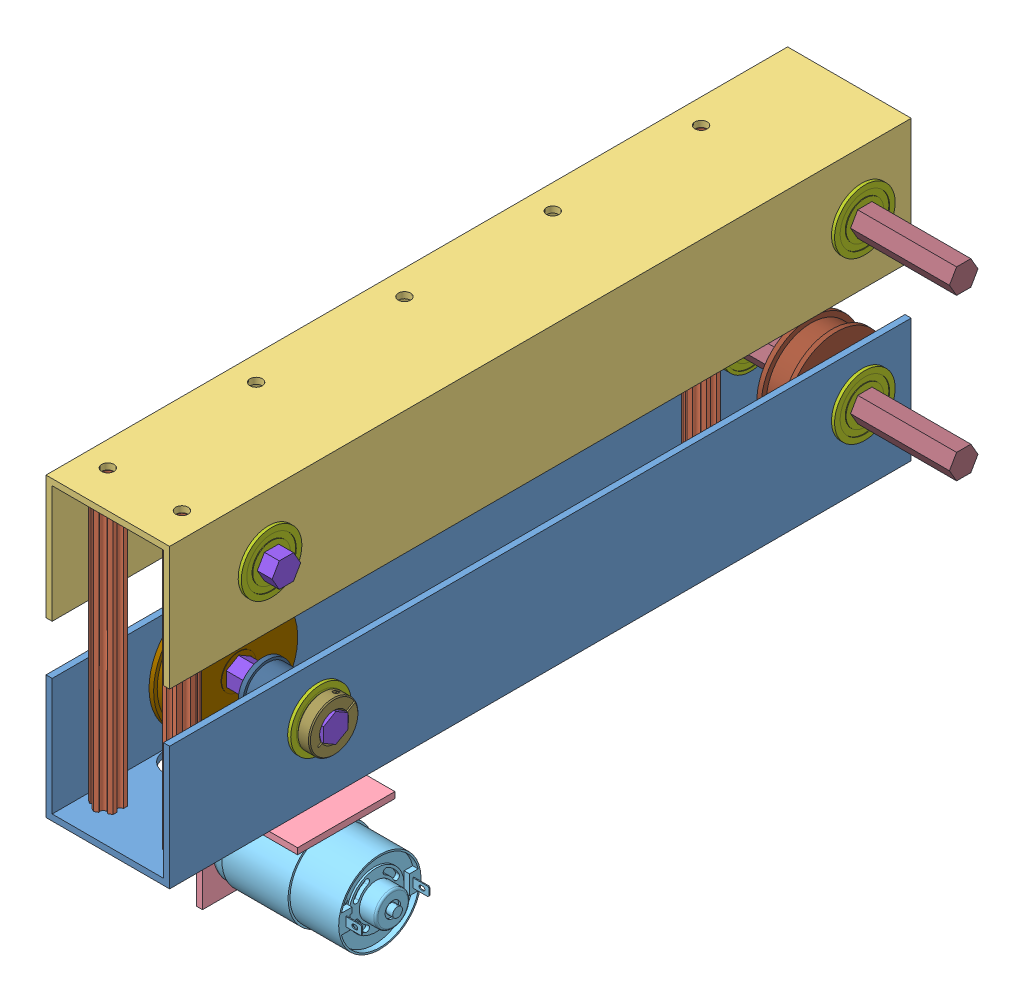
SolidWorks assembly 2018-402-A, configuration Default. Lengths in mm.
Overall size (127 204.4 381.04).
28 component instances, 13 part files, 80 mates.
Components (placement in the parent):
- 2018-402-D004-1: 2018-402-D004 [Default] at (114.5384 101.9763 135.5684) size (63.5 63.5 381)
- 2018-402-D021-1: 2018-402-D021 [Default] at (127.2384 251.2013 497.5184) x (0 0 -1) z (0 -1 0) size (14.66 12.7 146.05)
- 2018-402-D021-2: 2018-402-D021 [Default] at (165.3384 251.2013 497.5184) x (1 0 0) z (0 -1 0) size (14.66 12.7 146.05)
- 2018-402-D021-3: 2018-402-D021 [Default] at (127.2384 251.2013 192.7184) x (0 0 -1) z (0 -1 0) size (14.66 12.7 146.05)
- 2018-402-D005-2: 2018-402-D005 [Default] at (178.0384 254.3763 135.5684) x (-1 0 0) z (0 0 1) size (63.5 63.5 381)
- 2018-402-D014-1: 2018-402-D014 [Default] at (140.5734 49.9763 465.3684) x (0 0 -1) z (-1 0 0) size (68.52 52 56.75)
- 2018-402-D013-2: 2018-402-D013 [Default] at (143.7484 73.9763 440.3684) x (1 0 0) z (0 -1 0) size (88 44.3 44.3)
- 2018-402-D016-1: 2018-402-D016 [Default] at (137.5038 73.9763 440.3684) x (0 -1 0) z (0 0 1) size (15.01 17.5 15.01)
- 2018-403-D005-1: 2018-403-D005 [Default] at (120.8884 140.0763 440.3684) x (0 -1 0) z (0 0 -1) size (31.12 7.94 31.12)
- 2018-403-D005-2: 2018-403-D005 [Default] at (171.6884 140.0763 440.3684) x (0 -1 0) z (0 0 1) size (31.12 7.94 31.12)
- 2018-402-D025-1: 2018-402-D025 [Default] at (103.4259 140.0936 440.3584) x (0 -0.5 -0.866025) z (0 -0.866025 0.5) size (14.66 83.82 12.7)
- 2018-402-D019-1: 2018-402-D019 [Default] at (140.501 140.0936 440.2568) x (0 -1 0) z (0 0 1) size (61.01 15.88 61.01)
- 2018-402-D017-1: 2018-402-D017 [Default] at (168.5515 140.0643 440.3076) x (0 -1 0) z (0 0 1) size (25.4 15.88 25.4)
- 2018-403-D005-5: 2018-403-D005 [Default] at (120.8884 140.0763 160.9684) x (0 0 1) z (0 -1 0) size (31.12 7.94 31.12)
- 2018-403-D005-6: 2018-403-D005 [Default] at (171.6884 140.0763 160.9684) x (0 -0.866025 0.5) z (0 0.5 0.866025) size (31.12 7.94 31.12)
- 2018-402-D025-3: 2018-402-D025 [Default] at (100.2509 140.0863 160.9742) x (0 0 -1) z (0 -1 0) size (14.66 83.82 12.7) (hidden)
- 2018-402-D018-1: 2018-402-D018 [Default] at (168.5515 140.0863 161.0329) x (0 0 -1) z (0 -1 0) size (51 15.88 51)
- 2018-403-D005-7: 2018-403-D005 [Default] at (120.8884 222.6263 465.7684) x (0 0 1) z (0 -1 0) size (31.12 7.94 31.12)
- 2018-403-D005-8: 2018-403-D005 [Default] at (171.6884 222.6263 465.7684) x (0 -0.866025 -0.5) z (0 -0.5 0.866025) size (31.12 7.94 31.12)
- 2018-403-D002-1: 2018-403-D002 [Default] at (109.0742 140.1669 440.2314) x (0 -0.5 -0.866025) z (1 0 0) size (25.39 25.4 7.82)
- 2018-403-D002-2: 2018-403-D002 [Default] at (183.0549 139.8736 440.2314) x (0 0.5 -0.866025) z (1 0 0) size (25.39 25.4 7.82)
- 2018-402-D023-2: 2018-402-D023 [Default] at (103.4259 140.0863 160.9742) x (0 0.866025 -0.5) z (0 -0.5 -0.866025) size (14.66 127 12.7)
- 2018-403-D002-3: 2018-403-D002 [Default] at (109.5219 140.2133 161.0475) x (0 -0.866025 -0.5) z (1 0 0) size (25.39 25.4 7.82)
- 2018-402-D025-4: 2018-402-D025 [Default] at (187.2459 222.6163 465.7627) x (0 -0.866025 0.5) z (0 -0.5 -0.866025) size (14.66 83.82 12.7)
- 2018-403-D005-9: 2018-403-D005 [Default] at (171.6884 222.6263 160.9684) x (0 0 1) z (0 1 0) size (31.12 7.94 31.12)
- 2018-403-D005-10: 2018-403-D005 [Default] at (120.8884 222.6263 160.9684) x (0 0 1) z (0 -1 0) size (31.12 7.94 31.12)
- 2018-402-D023-3: 2018-402-D023 [Default] at (230.4259 222.6163 160.9742) x (0 -0.866025 -0.5) z (0 0.5 -0.866025) size (14.66 127 12.7)
- 2018-403-D002-4: 2018-403-D002 [Default] at (109.5219 222.6163 465.9093) x (0 -0.866025 -0.5) z (-1 0 0) size (25.39 25.4 7.82)
Mates (geometry in assembly coordinates):
- Concentric1: concentric anti-aligned: cylinder of 2018-402-D004-1 through (127.2384 165.4763 497.5184) axis (0 -1 0) radius 3.175; cylinder of 2018-402-D021-1 through (127.2384 -53.5987 497.5184) axis (0 1 0) radius 2.9337
- Coincident1: coincident anti-aligned: plane of 2018-402-D004-1 through (117.7134 105.1513 516.5684) normal (0 1 0); plane of 2018-402-D021-1 through (130.4134 105.1513 492.0192) normal (0 -1 0)
- Parallel1: parallel anti-aligned: plane of 2018-402-D004-1 through (114.5384 101.9763 516.5684) normal (-1 0 0); plane of 2018-402-D021-1 through (127.2384 251.2013 497.5184) normal (1 0 0)
- Concentric2: concentric anti-aligned: cylinder of 2018-402-D004-1 through (165.3384 165.4763 497.5184) axis (0 -1 0) radius 3.175; cylinder of 2018-402-D021-2 through (165.3384 -53.5987 497.5184) axis (0 1 0) radius 2.9337
- Coincident3: coincident anti-aligned: plane of 2018-402-D004-1 through (117.7134 105.1513 516.5684) normal (0 1 0); plane of 2018-402-D021-2 through (170.8377 105.1513 500.6934) normal (0 -1 0)
- Parallel2: parallel anti-aligned: plane of 2018-402-D004-1 through (114.5384 101.9763 516.5684) normal (-1 0 0); plane of 2018-402-D021-2 through (165.3384 251.2013 497.5184) normal (1 0 0)
- Concentric3: concentric anti-aligned: cylinder of 2018-402-D004-1 through (127.2384 165.4763 192.7184) axis (0 -1 0) radius 3.175; cylinder of 2018-402-D021-3 through (127.2384 -53.5987 192.7184) axis (0 1 0) radius 2.9337
- Coincident5: coincident anti-aligned: plane of 2018-402-D004-1 through (117.7134 105.1513 516.5684) normal (0 1 0); plane of 2018-402-D021-3 through (130.4134 105.1513 187.2192) normal (0 -1 0)
- Parallel3: parallel anti-aligned: plane of 2018-402-D004-1 through (114.5384 101.9763 516.5684) normal (-1 0 0); plane of 2018-402-D021-3 through (127.2384 251.2013 192.7184) normal (1 0 0)
- Concentric4: concentric aligned: cylinder of 2018-402-D021-2 through (165.3384 -53.5987 497.5184) axis (0 1 0) radius 2.9337; cylinder of 2018-402-D005-2 through (165.3384 190.8763 497.5184) axis (0 1 0) radius 3.175
- Coincident7: coincident anti-aligned: plane of 2018-402-D021-2 through (170.8377 251.2013 500.6934) normal (0 1 0); plane of 2018-402-D005-2 through (174.8634 251.2013 516.5684) normal (0 -1 0)
- Concentric5: concentric aligned: cylinder of 2018-402-D021-1 through (127.2384 -53.5987 497.5184) axis (0 1 0) radius 2.9337; cylinder of 2018-402-D005-2 through (127.2384 190.8763 497.5184) axis (0 1 0) radius 3.175
- Coincident11: coincident anti-aligned: plane of 2018-402-D004-1 through (114.5384 101.9763 516.5684) normal (0 -1 0); plane of 2018-402-D014-1 through (140.5734 101.9763 415.3684) normal (0 1 0)
- Coincident14: coincident anti-aligned: plane of 2018-402-D014-1 through (143.7484 98.8013 415.3684) normal (1 0 0); plane of 2018-402-D013-2 through (143.7484 73.9763 449.2684) normal (-1 0 0)
- Concentric9: concentric aligned: cylinder of 2018-402-D014-1 through (192.5734 73.9763 454.8684) axis (-1 0 0) radius 2; cylinder of 2018-402-D013-2 through (143.7484 73.9763 454.8684) axis (-1 0 0) radius 1.65
- Concentric10: concentric aligned: cylinder of 2018-402-D014-1 through (192.5734 73.9763 425.8684) axis (-1 0 0) radius 2; cylinder of 2018-402-D013-2 through (143.7484 73.9763 425.8684) axis (-1 0 0) radius 1.65
- Concentric11: concentric anti-aligned: cylinder of 2018-402-D013-2 through (143.7484 73.9763 440.3684) axis (-1 0 0) radius 2.5; cylinder of 2018-402-D016-1 through (192.5038 73.9763 440.3684) axis (1 0 0) radius 2.286
- Distance3: distance = 0.254 mm anti-aligned: plane of 2018-402-D016-1 through (138.4944 73.9763 438.0824) normal (1 0 0); plane of 2018-402-D013-2 through (138.7484 73.9763 442.8684) normal (-1 0 0)
- Parallel7: parallel aligned: plane of 2018-402-D004-1 through (114.5384 101.9763 516.5684) normal (0 -1 0); plane of 2018-402-D016-1 through (137.5038 73.9763 440.3684) normal (0 -1 0)
- Concentric12: concentric aligned: cylinder of 2018-402-D004-1 through (178.0384 140.0763 440.3684) axis (-1 0 0) radius 14.2875; cylinder of 2018-403-D005-1 through (120.8884 140.0763 440.3684) axis (-1 0 0) radius 14.2748
- Coincident20: coincident anti-aligned: plane of 2018-402-D004-1 through (114.5384 101.9763 516.5684) normal (-1 0 0); plane of 2018-403-D005-1 through (114.5384 124.5188 440.3684) normal (1 0 0)
- Parallel8: parallel aligned: plane of 2018-402-D004-1 through (114.5384 101.9763 516.5684) normal (0 -1 0); plane of 2018-403-D005-1 through (120.8884 140.0763 440.3684) normal (0 -1 0)
- Concentric13: concentric anti-aligned: cylinder of 2018-402-D004-1 through (178.0384 140.0763 440.3684) axis (-1 0 0) radius 14.2875; cylinder of 2018-403-D005-2 through (171.6884 140.0763 440.3684) axis (1 0 0) radius 14.2748
- Coincident22: coincident anti-aligned: plane of 2018-402-D004-1 through (178.0384 165.4763 516.5684) normal (1 0 0); plane of 2018-403-D005-2 through (178.0384 124.5188 440.3684) normal (-1 0 0)
- Parallel9: parallel aligned: plane of 2018-402-D004-1 through (114.5384 101.9763 516.5684) normal (0 -1 0); plane of 2018-403-D005-2 through (171.6884 140.0763 440.3684) normal (0 -1 0)
- Coincident24: coincident anti-aligned: plane of 2018-403-D005-1 through (120.8884 143.7482 446.7284) normal (0 -0.866025 -0.5); plane of 2018-402-D025-1 through (187.2459 147.426 440.3584) normal (0 0.866025 0.5)
- Coincident25: coincident anti-aligned: plane of 2018-403-D005-1 through (120.8884 143.7482 434.0084) normal (0 0 1); plane of 2018-402-D025-1 through (187.2459 136.4274 434.0084) normal (0 0 -1)
- Distance4: distance = 9.525 mm aligned: plane of 2018-402-D025-1 through (103.4259 140.0936 440.3584) normal (-1 0 0); plane of 2018-403-D005-1 through (112.9509 133.7263 440.3684) normal (-1 0 0)
- Coincident27: coincident anti-aligned: plane of 2018-402-D025-1 through (187.2459 136.4274 446.7084) normal (0 -0.866025 0.5); plane of 2018-402-D019-1 through (121.4129 136.3981 446.6576) normal (0 0.866025 -0.5)
- Coincident28: coincident anti-aligned: plane of 2018-402-D025-1 through (187.2459 147.426 440.3584) normal (0 0.866025 0.5); plane of 2018-402-D019-1 through (121.4129 147.4846 440.2568) normal (0 -0.866025 -0.5)
- Distance15: distance = 1.016 mm aligned: plane of 2018-402-D016-1 through (123.0004 73.9763 434.6407) normal (1 0 0); plane of 2018-402-D019-1 through (124.0164 140.0936 411.6056) normal (1 0 0)
- Coincident31: coincident anti-aligned: plane of 2018-402-D025-1 through (187.2459 143.7598 446.7084) normal (0 0 1); plane of 2018-402-D017-1 through (149.4634 143.7598 446.7084) normal (0 0 -1)
- Coincident32: coincident anti-aligned: plane of 2018-402-D025-1 through (187.2459 147.426 440.3584) normal (0 0.866025 0.5); plane of 2018-402-D017-1 through (149.4634 147.4553 440.3076) normal (0 -0.866025 -0.5)
- Distance6: distance = 6.35 mm anti-aligned: plane of 2018-402-D017-1 through (165.3384 140.0643 437.7676) normal (1 0 0); plane of 2018-403-D005-2 through (171.6884 130.4243 440.3684) normal (-1 0 0)
- Concentric16: concentric aligned: cylinder of 2018-402-D004-1 through (266.9384 140.0763 160.9684) axis (-1 0 0) radius 14.2875; cylinder of 2018-403-D005-5 through (120.8884 140.0763 160.9684) axis (-1 0 0) radius 14.2748
- Coincident44: coincident anti-aligned: plane of 2018-402-D004-1 through (114.5384 101.9763 516.5684) normal (-1 0 0); plane of 2018-403-D005-5 through (114.5384 140.0763 176.5259) normal (1 0 0)
- Parallel12: parallel anti-aligned: plane of 2018-402-D004-1 through (114.5384 101.9763 135.5684) normal (0 0 -1); plane of 2018-403-D005-5 through (120.8884 140.0763 160.9684) normal (0 0 1)
- Concentric17: concentric anti-aligned: cylinder of 2018-402-D004-1 through (266.9384 140.0763 160.9684) axis (-1 0 0) radius 14.2875; cylinder of 2018-403-D005-6 through (171.6884 140.0763 160.9684) axis (1 0 0) radius 14.2748
- Coincident46: coincident anti-aligned: plane of 2018-402-D004-1 through (178.0384 165.4763 516.5684) normal (1 0 0); plane of 2018-403-D005-6 through (178.0384 126.6031 168.7472) normal (-1 0 0)
- Coincident47: coincident aligned: plane of 2018-403-D005-5 through (120.8884 140.0763 168.3123) normal (0 -0.5 -0.866025); plane of 2018-403-D005-6 through (171.6884 146.4363 164.6404) normal (0 -0.5 -0.866025)
- Coincident48: coincident anti-aligned: plane of 2018-403-D005-5 through (120.8884 140.0763 168.3123) normal (0 -0.5 -0.866025); plane of 2018-402-D025-3 through (184.0709 146.4363 164.6404) normal (0 0.5 0.866025)
- Coincident49: coincident anti-aligned: plane of 2018-403-D005-5 through (120.8884 146.4363 164.6404) normal (0 -1 0); plane of 2018-402-D025-3 through (184.0709 146.4363 157.308) normal (0 1 0)
- Distance10: distance = 12.7 mm aligned: plane of 2018-402-D025-3 through (100.2509 140.0863 160.9742) normal (-1 0 0); plane of 2018-403-D005-5 through (112.9509 140.0763 167.3184) normal (-1 0 0)
- Coincident51: coincident anti-aligned: plane of 2018-402-D025-3 through (184.0709 133.7363 157.308) normal (0 -0.5 -0.866025); plane of 2018-402-D018-1 through (149.4634 133.6855 157.3374) normal (0 0.5 0.866025)
- Coincident52: coincident anti-aligned: plane of 2018-402-D025-3 through (184.0709 140.0863 153.6419) normal (0 0.5 -0.866025); plane of 2018-402-D018-1 through (149.4634 140.0863 153.6419) normal (0 -0.5 0.866025)
- Coincident53: coincident aligned: plane of 2018-402-D017-1 through (162.7349 140.0643 428.8522) normal (-1 0 0); plane of 2018-402-D018-1 through (162.7349 163.0098 161.0329) normal (-1 0 0)
- Concentric18: concentric aligned: cylinder of 2018-402-D005-2 through (178.0384 222.6263 465.7684) axis (-1 0 0) radius 14.2875; cylinder of 2018-403-D005-7 through (120.8884 222.6263 465.7684) axis (-1 0 0) radius 14.2748
- Coincident54: coincident anti-aligned: plane of 2018-402-D005-2 through (114.5384 190.8763 516.5684) normal (-1 0 0); plane of 2018-403-D005-7 through (114.5384 222.6263 481.3259) normal (1 0 0)
- Parallel13: parallel aligned: plane of 2018-402-D005-2 through (178.0384 254.3763 516.5684) normal (0 0 1); plane of 2018-403-D005-7 through (120.8884 222.6263 465.7684) normal (0 0 1)
- Concentric19: concentric anti-aligned: cylinder of 2018-402-D005-2 through (178.0384 222.6263 465.7684) axis (-1 0 0) radius 14.2875; cylinder of 2018-403-D005-8 through (171.6884 222.6263 465.7684) axis (1 0 0) radius 14.2748
- Coincident56: coincident anti-aligned: plane of 2018-402-D005-2 through (178.0384 254.3763 516.5684) normal (1 0 0); plane of 2018-403-D005-8 through (178.0384 209.1531 457.9897) normal (-1 0 0)
- Coincident57: coincident aligned: plane of 2018-403-D005-7 through (120.8884 222.6263 458.4245) normal (0 0.5 0.866025); plane of 2018-403-D005-8 through (171.6884 216.2663 462.0965) normal (0 0.5 0.866025)
- Coincident58: coincident anti-aligned: plane of 2018-402-D025-1 through (187.2459 143.7598 446.7084) normal (0 0 1); plane of 2018-403-D002-1 through (105.8992 143.9064 446.7084) normal (0 0 -1)
- Coincident59: coincident anti-aligned: plane of 2018-402-D025-1 through (187.2459 136.4274 446.7084) normal (0 -0.866025 0.5); plane of 2018-403-D002-1 through (105.8992 136.4274 446.7084) normal (0 0.866025 -0.5)
- Distance11: distance = 2.4733 mm aligned: plane of 2018-403-D002-1 through (105.8992 140.1669 440.2314) normal (-1 0 0); plane of 2018-402-D025-1 through (103.4259 140.0936 440.3584) normal (-1 0 0)
- Coincident61: coincident anti-aligned: plane of 2018-402-D025-1 through (187.2459 143.7598 446.7084) normal (0 0 1); plane of 2018-403-D002-2 through (179.8799 143.6131 446.7084) normal (0 0 -1)
- Distance12: distance = 0.254 mm anti-aligned: plane of 2018-403-D005-2 through (179.6259 133.7263 440.3684) normal (1 0 0); plane of 2018-403-D002-2 through (179.8799 139.8736 440.2314) normal (-1 0 0)
- Coincident65: coincident anti-aligned: plane of 2018-402-D025-1 through (187.2459 143.7598 434.0084) normal (0 0.866025 -0.5); plane of 2018-403-D002-2 through (179.8799 143.6131 433.7544) normal (0 -0.866025 0.5)
- Coincident66: coincident anti-aligned: plane of 2018-403-D005-5 through (120.8884 140.0763 168.3123) normal (0 -0.5 -0.866025); plane of 2018-402-D023-2 through (230.4259 146.4363 164.6404) normal (0 0.5 0.866025)
- Coincident67: coincident anti-aligned: plane of 2018-403-D005-5 through (120.8884 146.4363 164.6404) normal (0 -1 0); plane of 2018-402-D023-2 through (230.4259 146.4363 157.308) normal (0 1 0)
- Distance13: distance = 9.525 mm aligned: plane of 2018-402-D023-2 through (103.4259 140.0863 160.9742) normal (-1 0 0); plane of 2018-403-D005-5 through (112.9509 140.0763 167.3184) normal (-1 0 0)
- Coincident69: coincident anti-aligned: plane of 2018-402-D023-2 through (230.4259 133.7363 157.308) normal (0 -0.5 -0.866025); plane of 2018-403-D002-3 through (106.3469 133.7363 157.308) normal (0 0.5 0.866025)
- Coincident70: coincident anti-aligned: plane of 2018-402-D023-2 through (230.4259 133.7363 164.6404) normal (0 -1 0); plane of 2018-403-D002-3 through (106.3469 133.7363 164.787) normal (0 1 0)
- Distance14: distance = 0.254 mm anti-aligned: plane of 2018-403-D002-3 through (112.6969 140.2133 161.0475) normal (1 0 0); plane of 2018-403-D005-5 through (112.9509 140.0763 167.3184) normal (-1 0 0)
- Concentric20: concentric anti-aligned: cylinder of 2018-402-D004-1 through (153.2734 165.4763 440.3684) axis (0 -1 0) radius 3.175; cylinder of 2018-402-D014-1 through (153.2734 49.9763 440.3684) axis (0 1 0) radius 3.175
- Coincident72: coincident anti-aligned: plane of 2018-403-D005-7 through (120.8884 222.6263 458.4245) normal (0 0.5 0.866025); plane of 2018-402-D025-4 through (103.4259 222.6163 458.4303) normal (0 -0.5 -0.866025)
- Coincident73: coincident anti-aligned: plane of 2018-403-D005-7 through (120.8884 216.2663 462.0965) normal (0 1 0); plane of 2018-402-D025-4 through (103.4259 216.2663 462.0965) normal (0 -1 0)
- Distance16: distance = 9.525 mm aligned: plane of 2018-402-D025-4 through (103.4259 222.6163 465.7627) normal (-1 0 0); plane of 2018-403-D005-7 through (112.9509 222.6263 472.1184) normal (-1 0 0)
- Concentric21: concentric anti-aligned: cylinder of 2018-402-D005-2 through (178.0384 222.6263 160.9684) axis (-1 0 0) radius 14.2875; cylinder of 2018-403-D005-9 through (171.6884 222.6263 160.9684) axis (1 0 0) radius 14.2748
- Coincident74: coincident anti-aligned: plane of 2018-402-D005-2 through (178.0384 254.3763 516.5684) normal (1 0 0); plane of 2018-403-D005-9 through (178.0384 222.6263 176.5259) normal (-1 0 0)
- Parallel14: parallel anti-aligned: plane of 2018-402-D005-2 through (178.0384 254.3763 135.5684) normal (0 0 -1); plane of 2018-403-D005-9 through (171.6884 222.6263 160.9684) normal (0 0 1)
- Concentric22: concentric aligned: cylinder of 2018-402-D005-2 through (178.0384 222.6263 160.9684) axis (-1 0 0) radius 14.2875; cylinder of 2018-403-D005-10 through (120.8884 222.6263 160.9684) axis (-1 0 0) radius 14.2748
- Coincident76: coincident anti-aligned: plane of 2018-402-D005-2 through (114.5384 190.8763 516.5684) normal (-1 0 0); plane of 2018-403-D005-10 through (114.5384 222.6263 176.5259) normal (1 0 0)
- Coincident77: coincident aligned: plane of 2018-403-D005-9 through (171.6884 222.6263 168.3123) normal (0 0.5 -0.866025); plane of 2018-403-D005-10 through (120.8884 216.2663 164.6404) normal (0 0.5 -0.866025)
- Coincident78: coincident anti-aligned: plane of 2018-403-D005-10 through (120.8884 216.2663 164.6404) normal (0 0.5 -0.866025); plane of 2018-402-D023-3 through (103.4259 216.2663 164.6404) normal (0 -0.5 0.866025)
- Coincident79: coincident anti-aligned: plane of 2018-403-D005-10 through (120.8884 216.2663 157.2965) normal (0 1 0); plane of 2018-402-D023-3 through (103.4259 216.2663 157.308) normal (0 -1 0)
- Distance17: distance = 9.525 mm aligned: plane of 2018-402-D023-3 through (103.4259 222.6163 160.9742) normal (-1 0 0); plane of 2018-403-D005-10 through (112.9509 222.6263 167.3184) normal (-1 0 0)
- Coincident81: coincident: plane of 2018-402-D025-4 through (103.4259 228.9663 462.0965) normal (0 0.5 -0.866025); plane of 2018-403-D002-4 through (111.6609 229.0933 462.1698) normal (0 -0.5 0.866025)
- Coincident82: coincident: plane of 2018-402-D025-4 through (103.4259 222.6163 458.4303) normal (0 -0.5 -0.866025); plane of 2018-403-D002-4 through (111.6609 222.6163 458.4303) normal (0 0.5 0.866025)
- Distance18: distance = 0.254 mm anti-aligned: plane of 2018-403-D002-4 through (112.6969 222.6163 465.9093) normal (1 0 0); plane of 2018-403-D005-7 through (112.9509 222.6263 472.1184) normal (-1 0 0)
